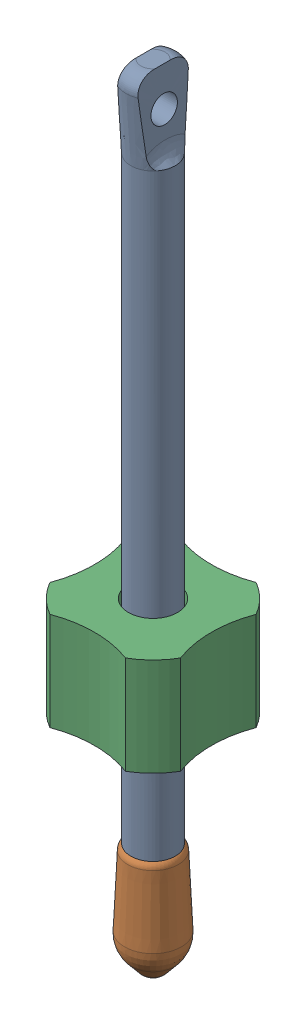
SolidWorks assembly MFG CW Spring Adj Asmbly, configuration Default. Lengths in mm.
Overall size (17.32 105.03 17.32).
5 component instances, 4 part files, 0 mates.
Components (placement in the parent):
- MFG CW Spring Adj Screw-1: MFG CW Spring Adj Screw [Default] at origin size (5.91 100.03 7.19)
- MFG CW M6 Rubber Screw Cap-1: MFG CW M6 Rubber Screw Cap [Default] at origin size (7.51 15 7.51)
- MFG CW Spring Adj Knob Asmbly-1: MFG CW Spring Adj Knob Asmbly [Default] at (0 -1.8867 0) size (17.32 13 17.32)
  - MFG CW Spring Adj Knob-1: MFG CW Spring Adj Knob [Default] at origin size (17.32 13 17.32)
  - M6 x 1 Hex Nut-1: M6 x 1 Hex Nut [Default] at (0 31.5 0) x (1 0 0) z (0 1 0) size (10 11.55 5)
